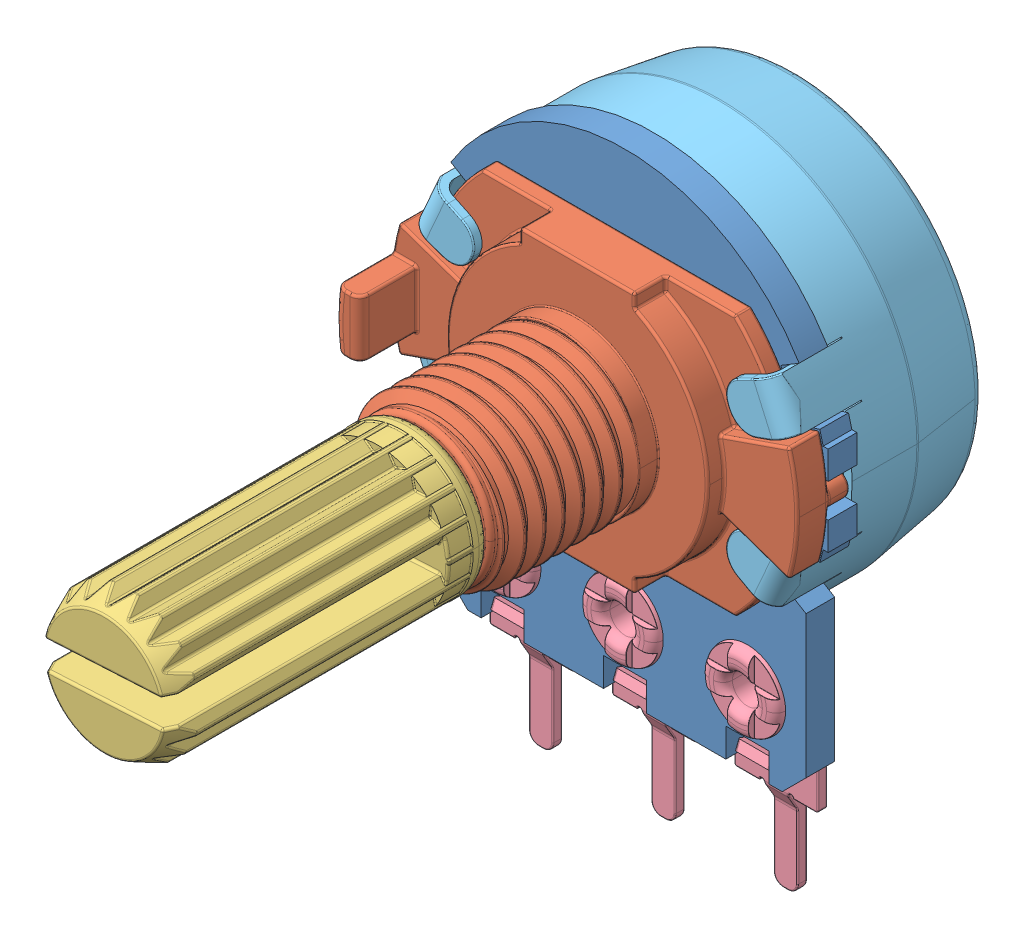
SolidWorks assembly pot, configuration Default. Lengths in mm.
Overall size (17.01 25.05 29.21).
9 component instances, 6 part files, 0 mates.
Components (placement in the parent):
- Assem1.STEP-1: Assem1.STEP [Default] at origin size (17.01 25.05 29.21)
  - pcb board.STEP-1: pcb board.STEP [Default] at origin size (17 20 1.2)
  - base metal.STEP-1: base metal.STEP [Default] at (0 0 1.2) size (17.01 10.9 9.8)
  - rotating rod metal.STEP-1: rotating rod metal.STEP [Default] at (0 0 9.8) x (0.998576 0.053354 0) z (0 0 1) size (6 6 25.8)
  - pin.STEP-1: pin.STEP [Default] at (0 -8.5 0) size (3.5 9.8 2.41)
  - pin.STEP-2: pin.STEP [Default] at (5.12 -8.5 0) size (3.5 9.8 2.41)
  - pin.STEP-3: pin.STEP [Default] at (-5.12 -8.5 0) size (3.5 9.8 2.41)
  - sheild metal.STEP-1: sheild metal.STEP [Default] at (0 0 -6) x (-1 0 0) z (0 0 1) size (16.6 16.6 8.5)
  - plastic base.STEP-1: plastic base.STEP [Default] at (0 0 -1.4) x (0.998576 0.053354 0) z (0 0 1) size (14 10.64 5.4)
